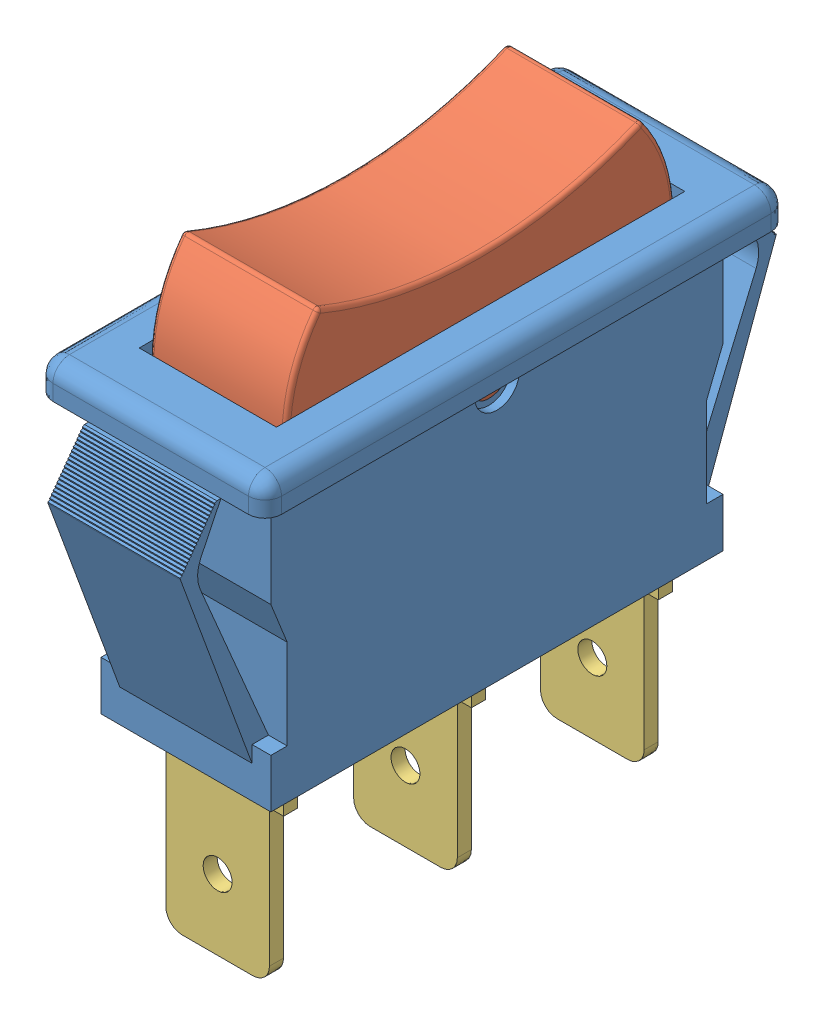
SolidWorks assembly Rocker Switch, configuration Default. Lengths in mm.
Overall size (14 35.35 36.5).
5 component instances, 3 part files, 12 mates.
Components (placement in the parent):
- Switch Body^Rocker Switch-1: Switch Body^Rocker Switch [Default] at (0 -4.9517 5.8721) size (14 19.23 36.5) (virtual)
- Switch Rocker^Rocker Switch-1: Switch Rocker^Rocker Switch [Default] at (0.025 9.7983 3.9321) size (10.35 9.42 23.8) (virtual)
- Terminal - Blade .25^Rocker Switch-1: Terminal - Blade .25^Rocker Switch [01] at (0 -3.4658 -19.4379) x (1 0 0) z (0 0 -1) size (8.08 15.75 1.95) (virtual)
- Terminal - Blade .25^Rocker Switch-2: Terminal - Blade .25^Rocker Switch [01] at (0 -3.4658 -7.9979) x (1 0 0) z (0 0 -1) size (8.08 15.75 1.95) (virtual)
- Terminal - Blade .25^Rocker Switch-3: Terminal - Blade .25^Rocker Switch [01] at (0 -3.4658 3.5021) x (1 0 0) z (0 0 -1) size (8.08 15.75 1.95) (virtual)
Mates (geometry in assembly coordinates):
- Concentric1: concentric: cylinder of Switch Body^Rocker Switch-1 through (-7 10.7983 -7.9679) axis (1 0 0) radius 1.375; cylinder of Switch Rocker^Rocker Switch-1 through (5.2 10.7983 -7.9679) axis (-1 0 0) radius 1
- Coincident10: coincident: plane of Switch Body^Rocker Switch-1 through (4.2 13.5283 4.5321) normal (-1 0 0); plane of Switch Rocker^Rocker Switch-1 through (4.2 13.4387 -10.3429) normal (1 0 0)
- Parallel1: parallel: plane of Switch Rocker^Rocker Switch-1 through (0.025 9.7983 3.9321) normal (0 1 0); plane of assembly through (0 0 0) normal (0 1 0)
- Coincident11: coincident: plane of Switch Body^Rocker Switch-1 through (-4.4 14.2793 -19.8679) normal (0 0 1); plane of Terminal - Blade .25^Rocker Switch-1 through (0.0508 -1.6497 -19.8679) normal (0 0 -1)
- Coincident12: coincident: plane of Terminal - Blade .25^Rocker Switch-1 through (0 -3.4658 -19.4379) normal (1 0 0); plane of assembly through (0 0 0) normal (1 0 0)
- Distance1: distance = 11.176 mm: plane of Switch Body^Rocker Switch-1 through (-5.2 -4.9517 -21.8079) normal (0 -1 0); plane of Terminal - Blade .25^Rocker Switch-1 through (2.159 -16.1277 -19.0079) normal (0 -1 0)
- Coincident13: coincident: plane of Terminal - Blade .25^Rocker Switch-1 through (2.159 -16.1277 -19.0079) normal (0 -1 0); plane of Terminal - Blade .25^Rocker Switch-2 through (2.159 -16.1277 -7.5679) normal (0 -1 0)
- Coincident14: coincident: plane of Terminal - Blade .25^Rocker Switch-1 through (2.159 -16.1277 -19.0079) normal (0 -1 0); plane of Terminal - Blade .25^Rocker Switch-3 through (2.159 -16.1277 3.9321) normal (0 -1 0)
- Coincident15: coincident: plane of Terminal - Blade .25^Rocker Switch-1 through (-3.175 -6.7297 -19.8679) normal (-1 0 0); plane of Terminal - Blade .25^Rocker Switch-2 through (-3.175 -6.7297 -8.4279) normal (-1 0 0)
- Coincident16: coincident: plane of Switch Body^Rocker Switch-1 through (-4.4 14.2793 -7.5679) normal (0 0 -1); plane of Terminal - Blade .25^Rocker Switch-2 through (0.0508 -1.6497 -7.5679) normal (0 0 1)
- Coincident17: coincident: plane of Switch Body^Rocker Switch-1 through (-4.4 14.2793 3.9321) normal (0 0 -1); plane of Terminal - Blade .25^Rocker Switch-3 through (0.0508 -1.6497 3.9321) normal (0 0 1)
- Coincident18: coincident: plane of Terminal - Blade .25^Rocker Switch-2 through (-3.175 -6.7297 -8.4279) normal (-1 0 0); plane of Terminal - Blade .25^Rocker Switch-3 through (-3.175 -6.7297 3.0721) normal (-1 0 0)
